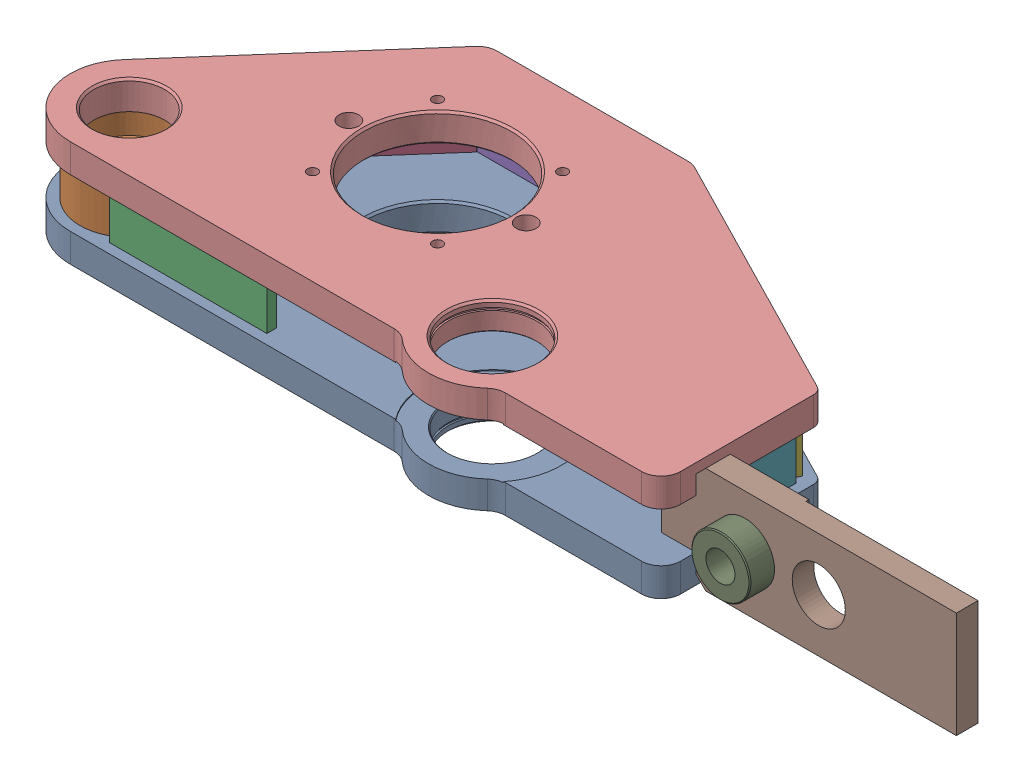
SolidWorks assembly g1_3_1_1_5, configuration 默认. Lengths in mm.
Overall size (926 108 318.6).
11 component instances, 11 part files, 0 mates.
Components (placement in the parent):
- g1_3_1_1_5-1_af1-1: g1_3_1_1_5-1_af1 [默认] at origin size (661 29 318.6)
- g1_3_1_1_5-2_af0-1: g1_3_1_1_5-2_af0 [默认] at (-213.2 29 0) size (100 50 100)
- g1_3_1_1_5-3-1: g1_3_1_1_5-3 [默认] at (-103.2 54 50) x (1 0 0) z (0 1 0) size (160 10 50)
- g1_3_1_1_5-4-1: g1_3_1_1_5-4 [默认] at (-149.9151 54 -132.7301) x (0 1 0) z (-0.659692 0 0.751536) size (50 10 223)
- g1_3_1_1_5-5-1: g1_3_1_1_5-5 [默认] at (20.5 54 -217) x (1 0 0) z (0 1 0) size (194 10 50)
- g1_3_1_1_5-6-1: g1_3_1_1_5-6 [默认] at (248.4498 54 -161.5242) x (0 1 0) z (0.890083 0 0.455798) size (50 10 284)
- g1_3_1_1_5-7-1: g1_3_1_1_5-7 [默认] at (377.8 54 -43.9) x (0 0 -1) z (0 1 0) size (87 10 50)
- g1_3_1_1_5-9_af0-1: g1_3_1_1_5-9_af0 [默认] at (502.8 54 24.6) x (1 0 0) z (0 1 0) size (300 25 108)
- g1_3_1_1_5-8-1: g1_3_1_1_5-8 [默认] at (437.8 54 49.6) x (1 0 0) z (0 1 0) size (60 50 60)
- g1_3_1_1_5-1_af0-1: g1_3_1_1_5-1_af0 [默认] at (0 79 0) size (661 29 318.6)
- g1_3_1_1_5_more-1: g1_3_1_1_5_more [默认] at origin size (139.2 108 206.2)
